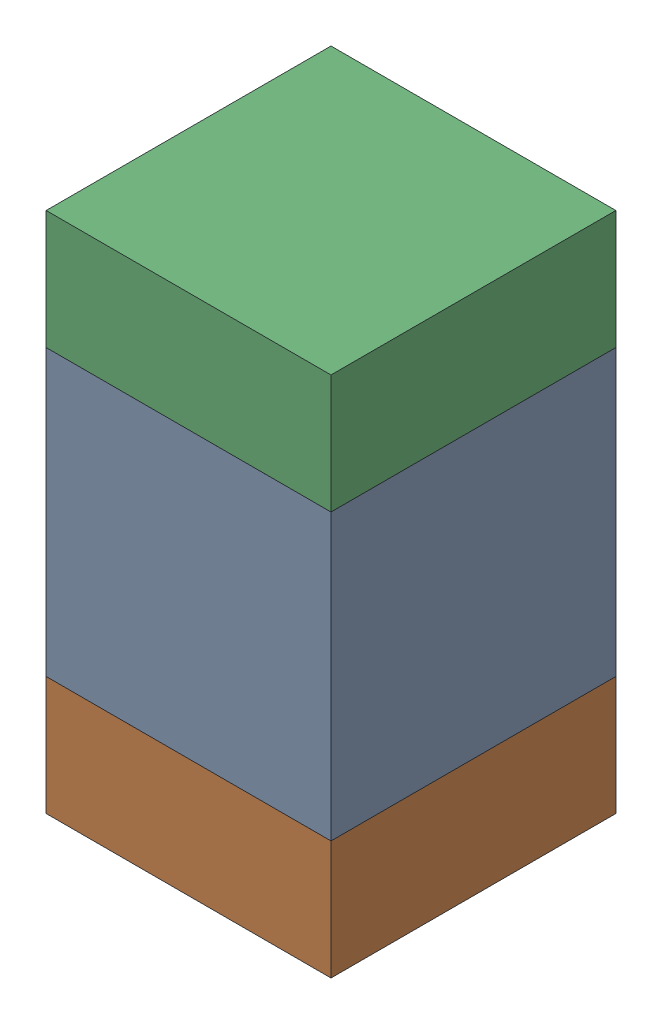
SolidWorks assembly C117_1PCB, configuration Default. Lengths in mm.
Overall size (0.6 1.1 0.6).
6 component instances, 2 part files, 0 mates.
Components (placement in the parent):
- 761606048-1: 761606048 [Default] at (114.7 113.6 0) size (0.6 0.6 0.6)
  - Extruded_9-1: Extruded_9 [Default] at origin size (0.6 0.6 0.6)
- 854785296-1: 854785296 [Default] at (114.7 113.175 0) size (0.6 0.25 0.6)
  - Extruded_10-1: Extruded_10 [Default] at origin size (0.6 0.25 0.6)
- 854785296-2: 854785296 [Default] at (114.7 114.025 0) size (0.6 0.25 0.6)
  - Extruded_10-1: Extruded_10 [Default] at origin size (0.6 0.25 0.6)
